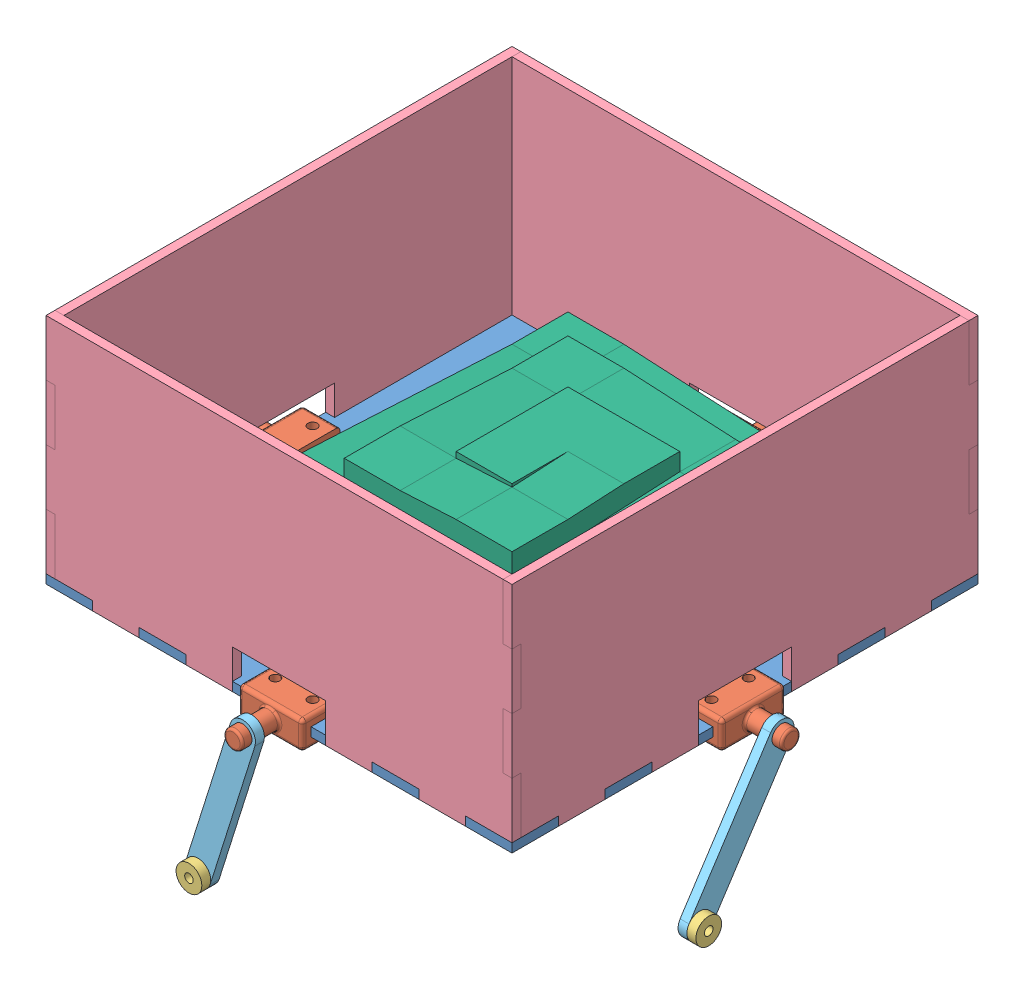
SolidWorks assembly plate, configuration Default. Lengths in mm.
Overall size (190.12 132.42 190.12).
14 component instances, 6 part files, 35 mates.
Components (placement in the parent):
- tilt-top-1: tilt-top [Default] at (-27.7721 66.3026 226.3823) size (158.75 3.05 158.75)
- platform-flange-1: platform-flange [Default] at (-30.7566 67.8901 147.0073) x (0 0 -1) z (1 0 0) size (21.84 9.53 25.53)
- platform-flange-2: platform-flange [Default] at (51.6029 67.8901 64.6478) size (21.84 9.53 25.53)
- platform-flange-3: platform-flange [Default] at (133.9624 67.7631 147.0073) x (0 0 1) z (-1 0 0) size (21.84 9.53 25.53)
- platform-flange-4: platform-flange [Default] at (51.6029 67.7631 229.3668) x (1 0 0) z (0 0 -1) size (21.84 9.53 25.53)
- servo-linkage-bushing-1: servo-linkage-bushing [Default] at (36.3524 19.3063 238.7648) x (0.652397 0.757877 0) z (0 0 1) size (8.76 8.76 3.05)
- servo-linkage-bushing-2: servo-linkage-bushing [Default] at (146.4084 25.2297 174.7842) x (0 -1 0) z (-1 0 0) size (8.76 8.76 3.05)
- top-wall-1: top-wall [Default] at (-27.7721 66.3026 226.3823) size (3.05 79.25 158.75)
- top-wall-2: top-wall [Default] at (130.9779 66.3026 226.3823) x (0 0 -1) z (1 0 0) size (3.05 79.25 158.75)
- top-wall-3: top-wall [Default] at (130.9779 66.3026 67.6323) x (-1 0 0) z (0 0 -1) size (3.05 79.25 158.75)
- top-wall-4: top-wall [Default] at (-27.7721 66.3026 67.6323) x (0 0 1) z (-1 0 0) size (3.05 79.25 158.75)
- servo-linkage-revised-1: servo-linkage-revised [Default] at (143.3604 25.2297 174.7842) x (0 0.546788 0.837271) z (0 -0.837271 0.546788) size (8.76 3.05 59.56)
- servo-linkage-revised-2: servo-linkage-revised [Default] at (51.6029 67.7631 238.7648) x (0.953874 -0.300208 0) z (0.300208 0.953874 0) size (8.76 3.05 59.56)
- ramp-1: ramp [Default] at (3.8509 69.3506 80.2053) x (0 0 1) z (-1 0 0) size (133.35 35.94 133.35)
Mates (geometry in assembly coordinates):
- Coincident1: coincident anti-aligned: plane of tilt-top-1 through (-27.7721 69.3506 226.3823) normal (0 1 0); plane of platform-flange-4 through (62.5249 69.3506 226.1918) normal (0 -1 0)
- Coincident2: coincident anti-aligned: plane of tilt-top-1 through (-27.7721 69.3506 226.3823) normal (0 1 0); plane of platform-flange-3 through (130.7874 69.3506 157.9293) normal (0 -1 0)
- Coincident3: coincident anti-aligned: plane of tilt-top-1 through (-27.7721 66.3026 226.3823) normal (0 -1 0); plane of platform-flange-1 through (-27.5816 66.3026 136.0853) normal (0 1 0)
- Concentric7: concentric anti-aligned: cylinder of tilt-top-1 through (45.2529 69.3506 72.7123) axis (0 -1 0) radius 1.397; cylinder of platform-flange-2 through (45.2529 63.1276 72.7123) axis (0 1 0) radius 1.5875
- Coincident5: coincident anti-aligned: plane of tilt-top-1 through (-27.7721 66.3026 226.3823) normal (0 -1 0); plane of platform-flange-2 through (62.5249 66.3026 67.8228) normal (0 1 0)
- Concentric8: concentric anti-aligned: cylinder of tilt-top-1 through (57.9529 69.3506 72.7123) axis (0 -1 0) radius 1.397; cylinder of platform-flange-2 through (57.9529 63.1276 72.7123) axis (0 1 0) radius 1.5875
- Concentric9: concentric anti-aligned: cylinder of tilt-top-1 through (-22.6921 69.3506 140.6573) axis (0 -1 0) radius 1.397; cylinder of platform-flange-1 through (-22.6921 63.1276 140.6573) axis (0 1 0) radius 1.5875
- Concentric10: concentric anti-aligned: cylinder of tilt-top-1 through (-22.6921 69.3506 153.3573) axis (0 -1 0) radius 1.397; cylinder of platform-flange-1 through (-22.6921 63.1276 153.3573) axis (0 1 0) radius 1.5875
- Concentric11: concentric aligned: cylinder of tilt-top-1 through (45.2529 69.3506 221.3023) axis (0 -1 0) radius 1.397; cylinder of platform-flange-4 through (45.2529 72.5256 221.3023) axis (0 -1 0) radius 1.5875
- Concentric12: concentric aligned: cylinder of tilt-top-1 through (57.9529 69.3506 221.3023) axis (0 -1 0) radius 1.397; cylinder of platform-flange-4 through (57.9529 72.5256 221.3023) axis (0 -1 0) radius 1.5875
- Concentric13: concentric anti-aligned: cylinder of tilt-top-1 through (125.8979 69.3506 153.3573) axis (0 -1 0) radius 1.397; cylinder of platform-flange-3 through (125.8979 63.0006 153.3573) axis (0 1 0) radius 1.5875
- Concentric14: concentric anti-aligned: cylinder of tilt-top-1 through (125.8979 69.3506 140.6573) axis (0 -1 0) radius 1.397; cylinder of platform-flange-3 through (125.8979 63.0006 140.6573) axis (0 1 0) radius 1.5875
- Coincident9: coincident anti-aligned: plane of tilt-top-1 through (-24.7241 69.3506 210.5073) normal (-1 0 0); plane of top-wall-1 through (-24.7241 66.3026 226.3823) normal (1 0 0)
- Coincident10: coincident aligned: plane of tilt-top-1 through (-27.7721 66.3026 226.3823) normal (0 -1 0); plane of top-wall-1 through (-24.7241 66.3026 210.5073) normal (0 -1 0)
- Coincident11: coincident anti-aligned: plane of tilt-top-1 through (-24.7241 69.3506 194.6323) normal (0 0 1); plane of top-wall-1 through (-24.7241 66.3026 194.6323) normal (0 0 -1)
- Coincident12: coincident anti-aligned: plane of tilt-top-1 through (115.1029 69.3506 223.3343) normal (0 0 1); plane of top-wall-2 through (130.9779 66.3026 223.3343) normal (0 0 -1)
- Coincident13: coincident aligned: plane of tilt-top-1 through (-27.7721 66.3026 226.3823) normal (0 -1 0); plane of top-wall-2 through (115.1029 66.3026 223.3343) normal (0 -1 0)
- Coincident14: coincident aligned: plane of tilt-top-1 through (130.9779 69.3506 226.3823) normal (1 0 0); plane of top-wall-2 through (130.9779 88.4006 223.3343) normal (1 0 0)
- Coincident15: coincident anti-aligned: plane of tilt-top-1 through (115.1029 69.3506 70.6803) normal (0 0 -1); plane of top-wall-4 through (-27.7721 66.3026 70.6803) normal (0 0 1)
- Coincident16: coincident aligned: plane of tilt-top-1 through (-27.7721 66.3026 226.3823) normal (0 -1 0); plane of top-wall-4 through (115.1029 66.3026 70.6803) normal (0 -1 0)
- Coincident17: coincident aligned: plane of tilt-top-1 through (130.9779 69.3506 83.5073) normal (1 0 0); plane of top-wall-4 through (130.9779 107.4506 70.6803) normal (1 0 0)
- Coincident21: coincident anti-aligned: plane of tilt-top-1 through (127.9299 69.3506 83.5073) normal (1 0 0); plane of top-wall-3 through (127.9299 66.3026 67.6323) normal (-1 0 0)
- Coincident22: coincident aligned: plane of tilt-top-1 through (115.1029 69.3506 67.6323) normal (0 0 -1); plane of top-wall-3 through (127.9299 88.4006 67.6323) normal (0 0 -1)
- Coincident23: coincident aligned: plane of tilt-top-1 through (-27.7721 66.3026 226.3823) normal (0 -1 0); plane of top-wall-3 through (127.9299 66.3026 83.5073) normal (0 -1 0)
- Distance1: distance = 6.35 mm anti-aligned: plane of platform-flange-4 through (51.6029 67.7631 242.0668) normal (0 0 1); plane of servo-linkage-revised-2 through (36.3524 19.3063 235.7168) normal (0 0 -1)
- Concentric15: concentric aligned: cylinder of platform-flange-4 through (51.6029 67.7631 242.0668) axis (0 0 1) radius 3.175; cylinder of servo-linkage-revised-2 through (51.6029 67.7631 235.7168) axis (0 0 1) radius 1.4605
- Distance2: distance = 6.35 mm anti-aligned: plane of servo-linkage-revised-1 through (140.3124 67.7631 147.0073) normal (-1 0 0); plane of platform-flange-3 through (146.6624 67.7631 147.0073) normal (1 0 0)
- Concentric16: concentric aligned: cylinder of platform-flange-3 through (146.6624 67.7631 147.0073) axis (1 0 0) radius 3.175; cylinder of servo-linkage-revised-1 through (140.3124 67.7631 147.0073) axis (1 0 0) radius 1.4605
- Coincident26: coincident anti-aligned: circle of servo-linkage-bushing-2; plane of servo-linkage-revised-1 through (143.3604 67.7631 147.0073) normal (1 0 0)
- Concentric17: concentric aligned: cylinder of servo-linkage-bushing-2 through (143.3604 25.2297 174.7842) axis (1 0 0) radius 1.4605; cylinder of servo-linkage-revised-1 through (140.3124 25.2297 174.7842) axis (1 0 0) radius 1.4605
- Coincident27: coincident aligned: circle of servo-linkage-bushing-1; plane of servo-linkage-revised-2 through (36.3524 19.3063 238.7648) normal (0 0 1)
- Concentric18: concentric anti-aligned: cylinder of servo-linkage-bushing-1 through (36.3524 19.3063 241.8128) axis (0 0 -1) radius 1.4605; cylinder of servo-linkage-revised-2 through (36.3524 19.3063 235.7168) axis (0 0 1) radius 1.4605
- Coincident28: coincident anti-aligned: plane of tilt-top-1 through (-27.7721 69.3506 226.3823) normal (0 1 0); plane of ramp-1 through (-15.1991 69.3506 213.5553) normal (0 -1 0)
- Distance3: distance = 9.525 mm anti-aligned: plane of ramp-1 through (-15.1991 69.3506 80.2053) normal (-1 0 0); plane of top-wall-1 through (-24.7241 66.3026 226.3823) normal (1 0 0)
- Distance4: distance = 9.525 mm anti-aligned: plane of ramp-1 through (99.1009 85.3245 80.2053) normal (0 0 -1); plane of top-wall-4 through (-27.7721 66.3026 70.6803) normal (0 0 1)
